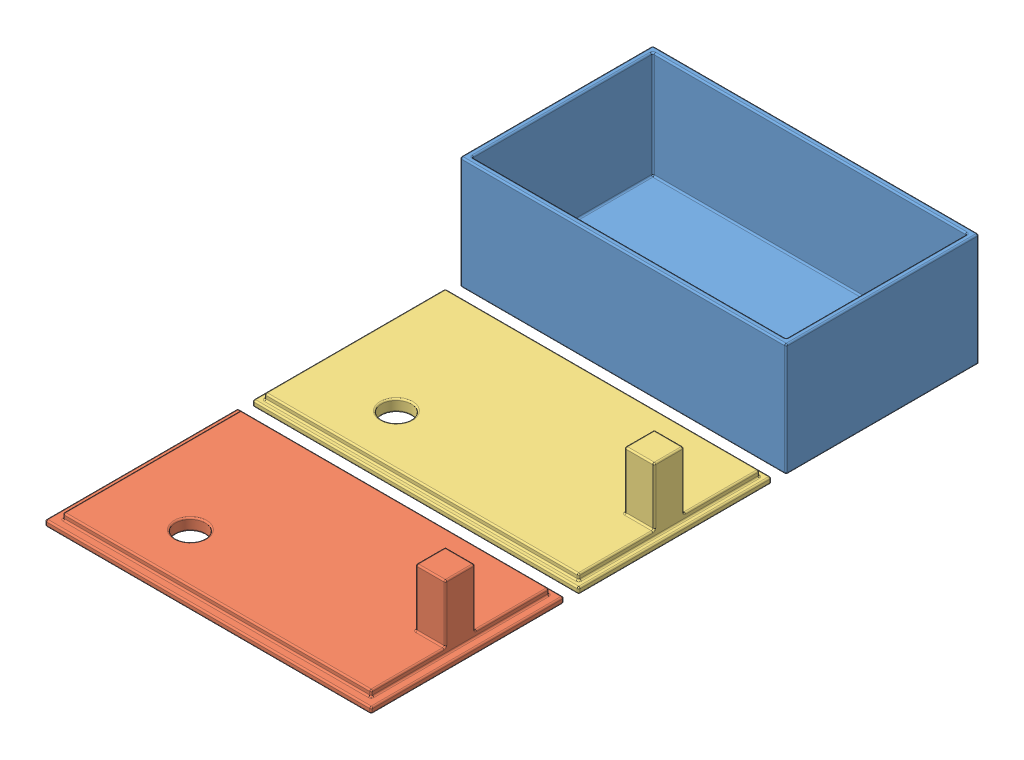
SolidWorks assembly Assem1, configuration Default. Lengths in mm.
Overall size (110 38 205).
3 component instances, 3 part files, 6 mates.
Components (placement in the parent):
- case-1: case [Default] at (-9.0614 34.6538 111.7038) size (110 38 65)
- lid_loose-1: lid_loose [Default] at (5.8052 34.6538 248.9785) size (110 23.5 65)
- lid_tight-1: lid_tight [Default] at (5.8052 34.6538 178.9785) size (110 23.5 65)
Mates (geometry in assembly coordinates):
- Coincident3: coincident: plane of case-1 through (57.8503 72.6538 74.645) normal (1 0 0); plane of lid_loose-1 through (57.8503 36.6538 214.645) normal (1 0 0)
- Coincident4: coincident: plane of lid_loose-1 through (57.8503 36.6538 214.645) normal (1 0 0); plane of lid_tight-1 through (57.8503 36.6538 144.645) normal (1 0 0)
- Distance1: distance = 5 mm: plane of case-1 through (-52.1497 72.6538 139.645) normal (0 0 1); plane of lid_tight-1 through (-52.1497 36.6538 144.645) normal (0 0 -1)
- Distance2: distance = 5 mm: plane of lid_loose-1 through (-52.1497 36.6538 214.645) normal (0 0 -1); plane of lid_tight-1 through (-52.1497 36.6538 209.645) normal (0 0 1)
- Coincident7: coincident: plane of case-1 through (-9.0614 34.6538 111.7038) normal (0 -1 0); plane of lid_tight-1 through (5.8052 34.6538 178.9785) normal (0 -1 0)
- Coincident8: coincident: plane of lid_loose-1 through (5.8052 34.6538 248.9785) normal (0 -1 0); plane of lid_tight-1 through (5.8052 34.6538 178.9785) normal (0 -1 0)
